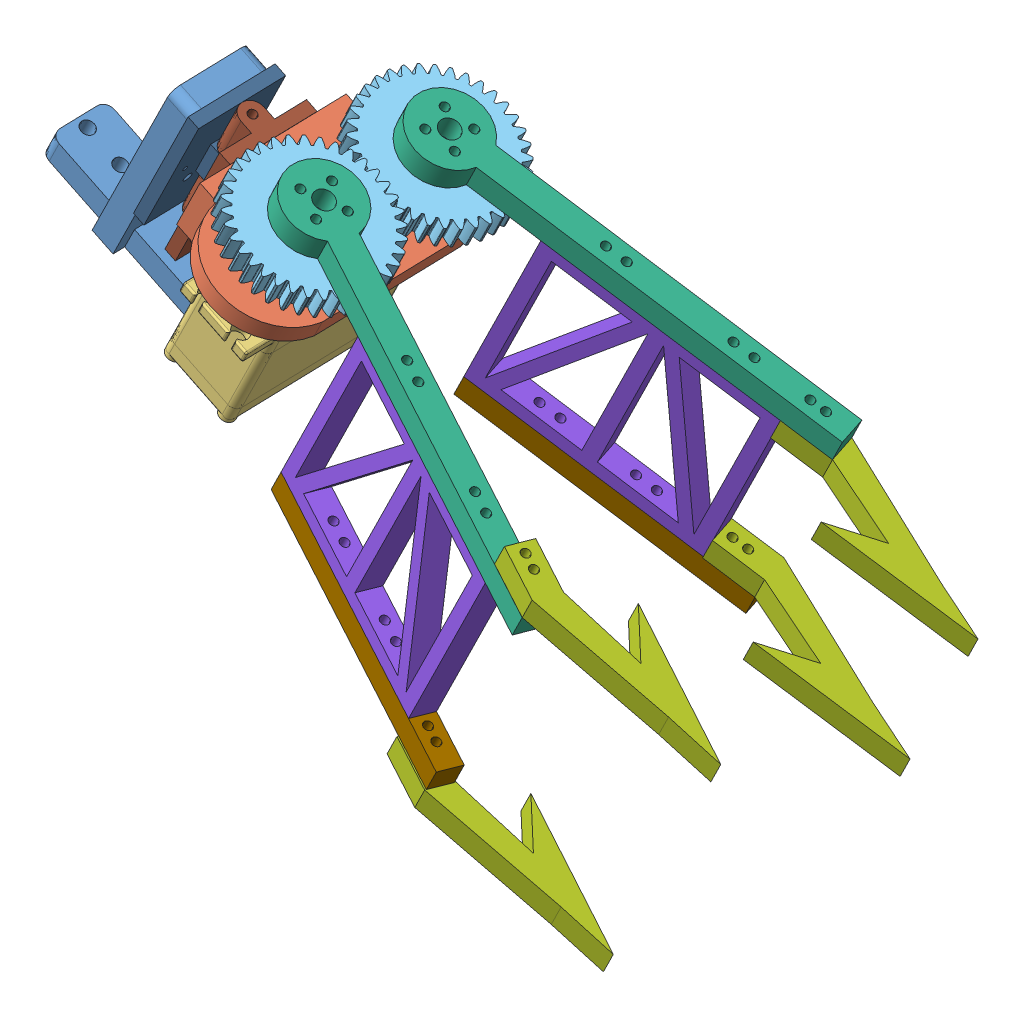
SolidWorks assembly NewGripper, configuration Default. Lengths in mm.
Overall size (212.16 139.64 170.09).
18 component instances, 11 part files, 50 mates.
Components (placement in the parent):
- GripperArmBracket-1: GripperArmBracket [Default] at (-74.3623 -36.9796 -7.8819) x (0.891866 -0.452119 -0.012815) z (0.000085 -0.028165 0.999603) size (55.88 50.8 21.59)
- Gripper_Connector-1: Gripper_Connector [Default] at (-40.1788 -2.7554 -19.3054) x (0.000085 -0.028165 0.999603) z (-0.891866 0.452119 0.012815) size (68 35 37)
- Servo 20kg elbow and gripper-1: Servo 20kg elbow and gripper [Default] at (-43.6988 -45.6755 1.4243) x (0.000085 -0.028165 0.999603) z (-0.891866 0.452119 0.012815) size (55.1 45.65 20.12)
- ServoHorn-1: ServoHorn [Default] at (-23.6448 -6.4296 12.4823) x (0.845587 -0.437602 0.305756) z (-0.283561 0.117085 0.95178) size (19.05 7.24 19.05)
- NewGear-1: NewGear [Default] at (-22.2087 -3.5991 12.562) x (-0.435082 0.245109 -0.866386) z (0.4523 0.891513 0.025081) size (37.89 37.89 6.35)
- NewGear-2: NewGear [Default] at (-23.6478 -5.4205 -23.3334) x (-0.740095 0.390876 -0.547243) z (0.4523 0.891513 0.025081) size (37.89 37.89 6.35)
- FingerTop-1: FingerTop [Default] at (-19.3366 2.062 12.7212) x (-0.435082 0.245109 -0.866386) z (0.778542 -0.380954 -0.498744) size (81.37 6.35 81.37)
- FingerTop-2: FingerTop [Default] at (-20.7757 0.2406 -23.1742) x (-0.767987 0.403621 -0.497279) z (0.453454 -0.205657 -0.867228) size (81.37 6.35 81.37)
- FingerOne-1: FingerOne [Default] at (56.7404 -30.0409 35.0698) x (-0.858162 0.442694 -0.259963) z (0.242863 -0.096057 -0.965293) size (57.15 6.35 20.95)
- FingerOne-2: FingerOne [Default] at (52.9067 -36.5139 -45.4778) x (-0.863689 0.430825 0.261594) z (0.222409 -0.139982 0.964852) size (57.15 6.35 20.95)
- Plate-1: Plate [Default] at (28.0422 -22.4707 30.3346) x (0.858162 -0.442694 0.259963) z (0.242863 -0.096057 -0.965293) size (58.42 50.04 6.35)
- Plate-2: Plate [Default] at (26.9613 -23.4783 -40.9473) x (-0.863689 0.430825 0.261594) z (0.222409 -0.139982 0.964852) size (58.42 50.04 6.35)
- FingerBottom-1: FingerBottom [Default] at (9.5294 -76.1624 24.4414) x (0.858162 -0.442694 0.259963) z (-0.242863 0.096057 0.965293) size (71.12 6.35 6.35)
- FingerOne-3: FingerOne [Default] at (25.5038 -91.6385 33.2897) x (-0.858162 0.442694 -0.259963) z (0.242863 -0.096057 -0.965293) size (57.15 6.35 20.95)
- FingerBottom-2: FingerBottom [Default] at (6.9415 -76.4846 -44.0227) x (0.863689 -0.430825 -0.261594) z (0.222409 -0.139982 0.964852) size (71.12 6.35 6.35)
- FingerOne-4: FingerOne [Default] at (33.1357 -75.4555 -46.6208) x (-0.863689 0.430825 0.261594) z (0.222409 -0.139982 0.964852) size (57.15 6.35 20.95)
- SpringLoadArm-1: SpringLoadArm [Default] at (-69.5031 -22.3426 12.0959) x (-0.000085 0.028165 -0.999603) z (0.891866 -0.452119 -0.012815) size (23.88 35.05 9.53)
- SpringLoadGripper-1: SpringLoadGripper [Default] at (-58.1774 -27.7482 -0.0001) x (0.000085 -0.028165 0.999603) z (-0.891866 0.452119 0.012815) size (23.88 35.05 9.53)
Mates (geometry in assembly coordinates):
- Concentric1: concentric aligned: circle of GripperArmBracket-1; circle of Gripper_Connector-1
- Parallel1: parallel aligned: plane of GripperArmBracket-1 through (-53.6494 9.0284 8.6587) normal (0.4523 0.891513 0.025081); plane of Gripper_Connector-1 through (-9.3776 -12.7656 -19.59) normal (0.4523 0.891513 0.025081)
- Concentric2: concentric aligned: circle of Gripper_Connector-1; circle of Servo 20kg elbow and gripper-1
- Parallel2: parallel aligned: plane of Gripper_Connector-1 through (-40.1788 -2.7554 -19.3054) normal (0.891866 -0.452119 -0.012815); plane of Servo 20kg elbow and gripper-1 through (-16.4157 -14.6778 22.3533) normal (0.891866 -0.452119 -0.012815)
- Parallel3: parallel anti-aligned: plane of GripperArmBracket-1 through (-46.5701 -44.38 7.1533) normal (0.4523 0.891513 0.025081); plane of Servo 20kg elbow and gripper-1 through (-43.6988 -45.6755 1.4243) normal (-0.4523 -0.891513 -0.025081)
- Coincident5: coincident anti-aligned: plane of GripperArmBracket-1 through (-46.5701 -44.38 7.1533) normal (0.4523 0.891513 0.025081); plane of Servo 20kg elbow and gripper-1 through (-43.6988 -45.6755 1.4243) normal (-0.4523 -0.891513 -0.025081)
- Concentric3: concentric aligned: circle of Gripper_Connector-1; circle of ServoHorn-1
- Coincident6: coincident anti-aligned: plane of Gripper_Connector-1 through (-9.3776 -12.7656 -19.59) normal (0.4523 0.891513 0.025081); plane of ServoHorn-1 through (-23.6448 -6.4296 12.4823) normal (-0.4523 -0.891513 -0.025081)
- Concentric4: concentric aligned: circle of ServoHorn-1; circle of NewGear-1
- Coincident8: coincident anti-aligned: plane of ServoHorn-1 through (-22.2087 -3.5991 12.562) normal (0.4523 0.891513 0.025081); plane of NewGear-1 through (-22.2087 -3.5991 12.562) normal (-0.4523 -0.891513 -0.025081)
- Concentric5: concentric aligned: circle of Gripper_Connector-1; circle of NewGear-2
- Coincident9: coincident anti-aligned: plane of Gripper_Connector-1 through (-9.3776 -12.7656 -19.59) normal (0.4523 0.891513 0.025081); plane of NewGear-2 through (-23.6478 -5.4205 -23.3334) normal (-0.4523 -0.891513 -0.025081)
- GearMate1: gear = 5.08 : 5.08 mm: circle of NewGear-1; circle of NewGear-2
- Concentric6: concentric aligned: circle of NewGear-1; circle of FingerTop-1
- Coincident11: coincident anti-aligned: plane of NewGear-1 through (-19.3366 2.062 12.7212) normal (0.4523 0.891513 0.025081); plane of FingerTop-1 through (-19.3366 2.062 12.7212) normal (-0.4523 -0.891513 -0.025081)
- Concentric7: concentric anti-aligned: circle of NewGear-1; circle of FingerTop-1
- Concentric8: concentric aligned: circle of NewGear-2; circle of FingerTop-2
- Coincident15: coincident anti-aligned: plane of NewGear-2 through (-20.7757 0.2406 -23.1742) normal (0.4523 0.891513 0.025081); plane of FingerTop-2 through (-20.7757 0.2406 -23.1742) normal (-0.4523 -0.891513 -0.025081)
- Lock1: lock: unknown of NewGear-2; unknown of FingerTop-2
- Concentric10: concentric aligned: circle of FingerTop-1; circle of FingerOne-1
- Concentric11: concentric aligned: circle of FingerTop-1; circle of FingerOne-1
- Coincident19: coincident anti-aligned: plane of FingerTop-1 through (-16.4645 7.7231 12.8805) normal (0.4523 0.891513 0.025081); plane of FingerOne-1 through (56.7404 -30.0409 35.0698) normal (-0.4523 -0.891513 -0.025081)
- Concentric12: concentric anti-aligned: circle of FingerTop-2; circle of FingerOne-2
- Concentric13: concentric anti-aligned: circle of FingerTop-2; circle of FingerOne-2
- Coincident22: coincident anti-aligned: plane of FingerTop-2 through (-20.7757 0.2406 -23.1742) normal (-0.4523 -0.891513 -0.025081); plane of FingerOne-2 through (52.9067 -36.5139 -45.4778) normal (0.4523 0.891513 0.025081)
- Concentric14: concentric anti-aligned: circle of FingerTop-1; circle of Plate-1
- Concentric15: concentric anti-aligned: circle of FingerTop-1; circle of Plate-1
- Concentric16: concentric anti-aligned: circle of FingerTop-1; circle of Plate-1
- Coincident26: coincident anti-aligned: plane of FingerTop-1 through (-19.3366 2.062 12.7212) normal (-0.4523 -0.891513 -0.025081); plane of Plate-1 through (4.5175 -10.1496 16.6115) normal (0.4523 0.891513 0.025081)
- Concentric17: concentric anti-aligned: circle of FingerTop-2; circle of Plate-2
- Concentric18: concentric anti-aligned: circle of FingerTop-2; circle of Plate-2
- Coincident29: coincident anti-aligned: plane of FingerTop-2 through (-20.7757 0.2406 -23.1742) normal (-0.4523 -0.891513 -0.025081); plane of Plate-2 through (53.602 -36.9515 -42.4617) normal (0.4523 0.891513 0.025081)
- Concentric19: concentric anti-aligned: circle of Plate-1; circle of FingerBottom-1
- Concentric20: concentric anti-aligned: circle of Plate-1; circle of FingerBottom-1
- Coincident34: coincident anti-aligned: plane of Plate-1 through (-18.1147 -54.7591 15.3564) normal (-0.4523 -0.891513 -0.025081); plane of FingerBottom-1 through (-19.6569 -54.1491 21.486) normal (0.4523 0.891513 0.025081)
- Concentric21: concentric aligned: circle of FingerBottom-1; circle of FingerOne-3
- Coincident37: coincident anti-aligned: plane of FingerBottom-1 through (-22.529 -59.8102 21.3268) normal (-0.4523 -0.891513 -0.025081); plane of FingerOne-3 through (28.3759 -85.9774 33.449) normal (0.4523 0.891513 0.025081)
- Concentric24: concentric aligned: circle of FingerBottom-1; circle of FingerOne-3
- Concentric26: concentric anti-aligned: circle of Plate-2; circle of FingerBottom-2
- Concentric27: concentric anti-aligned: circle of Plate-2; circle of FingerBottom-2
- Coincident43: coincident anti-aligned: plane of Plate-2 through (30.9698 -81.5611 -43.7167) normal (-0.4523 -0.891513 -0.025081); plane of FingerBottom-2 through (-19.4869 -56.3923 -28.4344) normal (0.4523 0.891513 0.025081)
- Concentric28: concentric anti-aligned: circle of FingerBottom-2; circle of FingerOne-4
- Concentric30: concentric anti-aligned: circle of FingerBottom-2; circle of FingerOne-4
- Coincident46: coincident anti-aligned: plane of FingerBottom-2 through (-19.4869 -56.3923 -28.4344) normal (0.4523 0.891513 0.025081); plane of FingerOne-4 through (30.2636 -81.1166 -46.7801) normal (-0.4523 -0.891513 -0.025081)
- Concentric31: concentric anti-aligned: circle of GripperArmBracket-1; circle of SpringLoadArm-1
- Concentric32: concentric anti-aligned: circle of GripperArmBracket-1; circle of SpringLoadArm-1
- Coincident49: coincident anti-aligned: plane of GripperArmBracket-1 through (-73.7542 -30.5994 7.5439) normal (0.891866 -0.452119 -0.012815); plane of SpringLoadArm-1 through (-69.5031 -22.3426 12.0959) normal (-0.891866 0.452119 0.012815)
- Concentric33: concentric anti-aligned: circle of SpringLoadArm-1; circle of SpringLoadGripper-1
- Coincident53: coincident anti-aligned: plane of Gripper_Connector-1 through (-44.6382 -0.4948 -19.2413) normal (-0.891866 0.452119 0.012815); plane of SpringLoadGripper-1 through (-58.1774 -27.7482 -0.0001) normal (0.891866 -0.452119 -0.012815)
- Coincident54: coincident anti-aligned: plane of SpringLoadArm-1 through (-50.899 -6.4751 3.7749) normal (0.4523 0.891513 0.025081); plane of SpringLoadGripper-1 through (-56.5647 -2.8172 -24.0726) normal (-0.4523 -0.891513 -0.025081)
